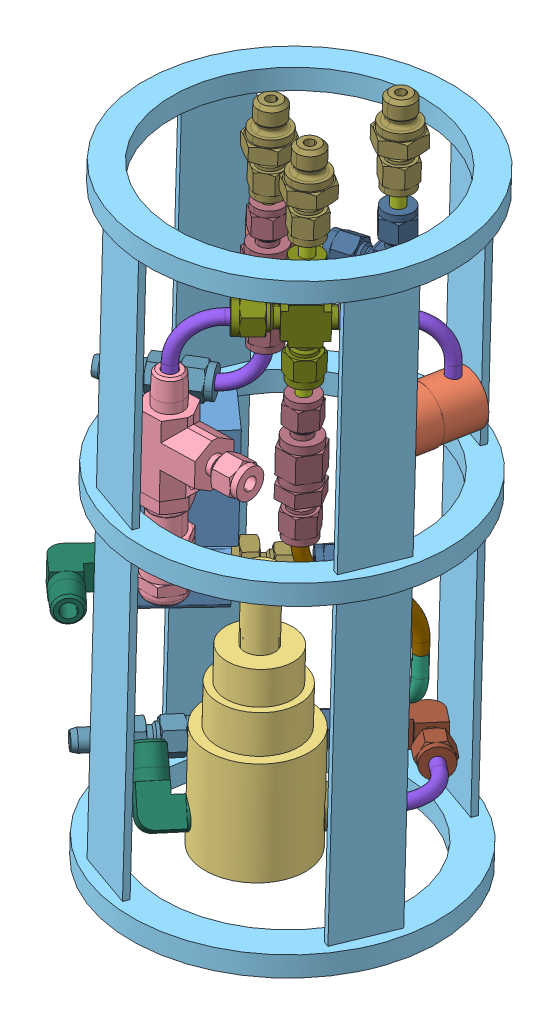
SolidWorks assembly assemblage pressurant bay, configuration Défaut. Lengths in mm.
Overall size (196.95 323.2 205.69).
39 component instances, 16 part files, 39 mates.
Components (placement in the parent):
- 132203_soleno_quart-1: 132203_soleno_quart [Défaut] at (-119.4235 -585.201 211.5274) x (-0.747467 -0.027365 -0.663735) z (0.664276 -0.022565 -0.747147) size (28 80.02 47.02)
- 132201_AG2029_soleno_8-1: 132201_AG2029_soleno_8 [Défaut] at (44.6422 -477.8039 184.1619) x (-0.988898 -0.010608 -0.148214) z (-0.005468 0.999371 -0.035044) size (26.06 49.78 26.06)
- 132201_AG2029_soleno_8-2: 132201_AG2029_soleno_8 [Défaut] at (-39.3498 -434.298 195.0532) x (-0.288649 -0.03513 -0.95679) z (-0.957419 0.004883 0.28866) size (26.06 49.78 26.06)
- 132202_Détendeur-1: 132202_Détendeur [Défaut] at (7.1335 -657.7663 254.7974) x (-0.783042 -0.026076 -0.621422) z (-0.005468 0.999371 -0.035044) size (50 50 118.8)
- SS-4R3A1-SwagelokCompany-3D-11-18-2022.stp-1: SS-4R3A1-SwagelokCompany-3D-11-18-2022.stp [Défaut] at (-26.3083 -491.3399 265.237) x (0.99971 0.004641 -0.023651) z (0.005468 -0.999371 0.035044) size (51.64 20.24 98.81)
- 132300_pressurant_bay_mockup-1: 132300_pressurant_bay_mockup [Défaut] at (-4.8119 -683.7166 228.9256) x (0.341839 -0.031065 -0.939245) z (0.939743 0.017116 0.341454) size (152.4 300 152.4)
- 132102_tuyau_180deg-2: 132102_tuyau_180deg [Défaut] at (20.7227 -597.9813 192.7678) x (-0.926897 -0.018217 -0.374875) z (-0.375277 0.030432 0.926413) size (36.35 28.17 6.35)
- 132103_tuyau_droit-2: 132103_tuyau_droit [Défaut] at (6.0364 -455.1823 182.1277) x (-0.005468 0.999371 -0.035044) z (-0.001435 0.035037 0.999385) size (30 6.35 6.35)
- 132103_tuyau_droit-3: 132103_tuyau_droit [Défaut] at (6.4308 -527.2611 184.6552) x (-0.005468 0.999371 -0.035044) z (-0.041186 -0.03524 -0.99853) size (30 6.35 6.35)
- 132103_tuyau_droit-4: 132103_tuyau_droit [Défaut] at (6.4876 -421.5338 227.8474) x (-0.005468 0.999371 -0.035044) z (-0.001435 0.035037 0.999385) size (30 6.35 6.35)
- 132103_tuyau_droit-5: 132103_tuyau_droit [Défaut] at (5.7292 -399.0439 180.1592) x (-0.005468 0.999371 -0.035044) z (-0.001435 0.035037 0.999385) size (30 6.35 6.35)
- 132103_tuyau_droit-7: 132103_tuyau_droit [Défaut] at (6.3506 -396.4974 226.9695) x (-0.005468 0.999371 -0.035044) z (0.996345 0.002458 -0.085384) size (30 6.35 6.35)
- 132103_tuyau_droit-9: 132103_tuyau_droit [Défaut] at (-23.2756 -392.0235 216.7844) x (-0.005468 0.999371 -0.035044) z (0.001495 0.035053 0.999384) size (30 6.35 6.35)
- 132103_tuyau_droit-12: 132103_tuyau_droit [Défaut] at (6.7101 -462.1929 229.2732) x (-0.005468 0.999371 -0.035044) z (0.919834 -0.00872 -0.392211) size (30 6.35 6.35)
- 132103_tuyau_droit-16: 132103_tuyau_droit [Défaut] at (-11.9207 -441.383 187.0384) x (0.957419 -0.004883 -0.28866) z (-0.209798 -0.698629 -0.684034) size (30 6.35 6.35)
- 132101_tuyau_90deg-4: 132101_tuyau_90deg [Défaut] at (30.286 -459.4562 204.3322) x (-0.688847 0.021639 0.724584) z (-0.724886 -0.028102 -0.688295) size (52.38 52.38 6.35)
- 132101_tuyau_90deg-5: 132101_tuyau_90deg [Défaut] at (-13.2667 -458.0881 250.1444) x (0.688847 -0.021639 -0.724584) z (0.724886 0.028102 0.688295) size (52.38 52.38 6.35)
- 132101_tuyau_90deg-6: 132101_tuyau_90deg [Défaut] at (-38.9599 -470.4239 229.9776) x (-0.839316 0.014464 0.543451) z (0.543616 0.032385 0.838709) size (52.38 52.38 6.35)
- 132105_tuyau_S_2-2: 132105_tuyau_S_2 [Défaut] at (34.5408 -582.1179 197.8443) x (-0.606708 0.024542 0.794546) z (-0.794906 -0.025607 -0.606192) size (51.2 56 6.4)
- 132006_raccord_T_4_SS-400-3-1: 132006_raccord_T_4_SS-400-3 [Défaut] at (-42.4245 -645.2228 233.0351) x (0.621944 -0.024043 -0.782692) z (-0.027001 0.998276 -0.052121) size (53.85 14.22 35.14)
- 132103_tuyau_droit-17: 132103_tuyau_droit [Défaut] at (3.8411 -647.0113 174.8117) x (0.621944 -0.024043 -0.782692) z (0.483638 -0.774308 0.408095) size (30 6.35 6.35)
- 132002_SS-400-9_raccord_L_4-1: 132002_SS-400-9_raccord_L_4 [Défaut] at (30.033 -645.7675 185.0656) x (-0.782596 -0.05355 -0.620223) z (0.621944 -0.024043 -0.782692) size (35.14 14.22 35.14)
- 132005_raccord_SW_G_4_SS-400-1-4RP-1: 132005_raccord_SW_G_4_SS-400-1-4RP [Défaut] at (5.7707 -406.6319 180.4252) x (-0.005468 0.999371 -0.035044) z (-0.009624 0.03499 0.999341) size (40.39 19.05 22)
- 132005_raccord_SW_G_4_SS-400-1-4RP-2: 132005_raccord_SW_G_4_SS-400-1-4RP [Défaut] at (-23.2018 -405.4989 217.257) x (-0.005468 0.999371 -0.035044) z (-0.009624 0.03499 0.999341) size (40.39 19.05 22)
- 132005_raccord_SW_G_4_SS-400-1-4RP-3: 132005_raccord_SW_G_4_SS-400-1-4RP [Défaut] at (6.3971 -404.9859 227.2671) x (-0.005468 0.999371 -0.035044) z (-0.009624 0.03499 0.999341) size (40.39 19.05 22)
- 132003_check_valve_SS-CHS4-25-1: 132003_check_valve_SS-CHS4-25 [Défaut] at (-23.1838 -408.7866 217.3722) x (0.005468 -0.999371 0.035044) z (-0.050941 0.034721 0.998098) size (61.72 17.46 20.16)
- 132010_SS-QF4-S-400_quick_fitting-1: 132010_SS-QF4-S-400_quick_fitting [Défaut] at (-37.4625 -489.6358 229.7489) x (-0.839316 0.014464 0.543451) z (-0.542446 -0.088602 -0.835406) size (44.96 14.3 16.5)
- 132006_raccord_T_4_SS-400-3-2: 132006_raccord_T_4_SS-400-3 [Défaut] at (5.8141 -414.5671 180.7035) x (0.005468 -0.999371 0.035044) z (0.957419 -0.004883 -0.28866) size (53.85 14.22 35.14)
- 132003_check_valve_SS-CHS4-25-2: 132003_check_valve_SS-CHS4-25 [Défaut] at (6.1248 -471.3388 182.6943) x (0.005468 -0.999371 0.035044) z (-0.406496 0.029797 0.913167) size (61.72 17.46 20.16)
- 132005_raccord_SW_G_4_SS-400-1-4RP-4: 132005_raccord_SW_G_4_SS-400-1-4RP [Défaut] at (-12.5558 -568.0822 207.72) x (-0.664276 0.022565 0.747147) z (-0.747318 0.001243 -0.664466) size (40.39 19.05 22)
- 132003_check_valve_SS-CHS4-25-3: 132003_check_valve_SS-CHS4-25 [Défaut] at (6.7652 -472.2552 229.626) x (0.005468 -0.999371 0.035044) z (-0.474344 0.028259 0.879886) size (61.72 17.46 20.16)
- 132006_raccord_T_4_SS-400-3-3: 132006_raccord_T_4_SS-400-3 [Défaut] at (6.5105 -541.8278 185.166) x (0.005468 -0.999371 0.035044) z (0.664276 -0.022565 -0.747147) size (53.85 14.22 35.14)
- 132007_SS-4-ME_raccord_L_NPT-3: 132007_SS-4-ME_raccord_L_NPT [Défaut] at (-29.1208 -621.4599 272.2373) x (0.49179 -0.765825 0.414312) z (-0.621944 0.024043 0.782692) size (33.53 13.72 33.53)
- 132010_SS-QF4-S-400_quick_fitting-2: 132010_SS-QF4-S-400_quick_fitting [Défaut] at (-43.6684 -645.1747 234.6004) x (-0.621944 0.024043 0.782692) z (-0.765639 0.191002 -0.61426) size (44.96 14.3 16.5)
- 132103_tuyau_droit-18: 132103_tuyau_droit [Défaut] at (-44.2794 -645.1511 235.3694) x (0.621944 -0.024043 -0.782692) z (0.778247 0.129642 0.61443) size (30 6.35 6.35)
- 132005_raccord_SW_G_4_SS-400-1-4RP-5: 132005_raccord_SW_G_4_SS-400-1-4RP [Défaut] at (39.6752 -644.0369 213.2161) x (-0.621944 0.024043 0.782692) z (-0.762062 -0.248509 -0.597917) size (40.39 19.05 22)
- 132101_tuyau_90deg-7: 132101_tuyau_90deg [Défaut] at (22.7076 -644.99 203.7515) x (-0.782596 -0.05355 -0.620223) z (0.027001 -0.998276 0.052121) size (52.38 52.38 6.35)
- 132007_SS-4-ME_raccord_L_NPT-4: 132007_SS-4-ME_raccord_L_NPT [Défaut] at (-53.1719 -566.7025 253.4032) x (-0.664276 0.022565 0.747147) z (-0.747342 -0.000323 -0.66444) size (33.53 13.72 33.53)
- 132009_SS-400-4_raccord_X_Sw-1: 132009_SS-400-4_raccord_X_Sw [Défaut] at (6.4389 -412.6201 227.5348) x (0.005468 -0.999371 0.035044) z (-0.688847 0.021639 0.724584) size (53.85 14.22 53.85)
Mates (geometry in assembly coordinates):
- Coaxiale62: concentric aligned: cylinder of tuyau droit basique-4 through (6.6566 -452.4163 228.9303) axis (-0.005468 0.999371 -0.035044) radius 3.175; cylinder of tuyau droit basique-12 through (6.8791 -493.0754 230.3561) axis (-0.005468 0.999371 -0.035044) radius 3.175
- Coaxiale63: concentric aligned: cylinder of tuyau droit basique-4 through (6.6566 -452.4163 228.9303) axis (-0.005468 0.999371 -0.035044) radius 3.175; cylinder of tuyau droit basique-7 through (6.5196 -427.3799 228.0524) axis (-0.005468 0.999371 -0.035044) radius 3.175
- Parallèle3: parallel aligned: cylinder of tuyau droit basique-7 through (6.5196 -427.3799 228.0524) axis (-0.005468 0.999371 -0.035044) radius 3.175; cylinder of tuyau droit basique-9 through (-23.1066 -422.9061 217.8674) axis (-0.005468 0.999371 -0.035044) radius 3.175
- Parallèle4: parallel aligned: cylinder of AG2029-2 through (-39.1054 -478.9699 196.6197) axis (-0.005468 0.999371 -0.035044) radius 13.03; cylinder of tuyau droit basique-2 through (6.2053 -486.0649 183.2107) axis (-0.005468 0.999371 -0.035044) radius 3.175
- Parallèle10: parallel anti-aligned: cylinder of tuyau droit basique-7 through (6.5196 -427.3799 228.0524) axis (-0.005468 0.999371 -0.035044) radius 3.175; cylinder of tuyau coudé 90deg-4 through (43.5119 -459.8717 190.4202) axis (0.005468 -0.999371 0.035044) radius 3.175
- Coaxiale94: concentric aligned: cone of AG2029-1 through (43.5402 -465.0412 190.6015) axis (0.005468 -0.999371 0.035044); cylinder of tuyau coudé 90deg-4 through (43.5119 -459.8717 190.4202) axis (0.005468 -0.999371 0.035044) radius 3.175
- Distance13: distance = 0 mm anti-aligned: plane of tuyau demi circulaire-2 through (34.5714 -587.7144 198.0405) normal (-0.005468 0.999371 -0.035044); plane of tuyau en S-2 through (34.5714 -587.7144 198.0405) normal (0.005468 -0.999371 0.035044)
- Coaxiale95: concentric anti-aligned: cylinder of tuyau demi circulaire-2 through (34.5714 -587.7144 198.0405) axis (0.005468 -0.999371 0.035044) radius 3.175; cylinder of tuyau en S-2 through (34.5714 -587.7144 198.0405) axis (-0.005468 0.999371 -0.035044) radius 3.2
- Coaxiale100: concentric anti-aligned: cylinder of SS-4R3A1-SwagelokCompany-3D-11-18-2022.stp-1 through (-26.4323 -468.6796 264.4424) axis (-0.005468 0.999371 -0.035044) radius 3.556; cylinder of tuyau coudé 90deg-5 through (-26.4926 -457.6726 264.0564) axis (0.005468 -0.999371 0.035044) radius 3.175
- Parallèle17: parallel aligned: cylinder of Détendeur Azote-1 through (6.8535 -606.5985 253.0031) axis (0.005468 -0.999371 0.035044) radius 25; line of pressurant_bay_mockup-1 through (-42.8298 -521.9796 281.5208) axis (0.005468 -0.999371 0.035044)
- Coaxiale110: concentric aligned: cylinder of 132006_raccord_T_4_SS-400-3-1 through (-37.6853 -645.406 227.0709) axis (0.621944 -0.024043 -0.782692) radius 3.175; cylinder of 132103_tuyau_droit-17 through (-15.3782 -646.2683 198.9984) axis (0.621944 -0.024043 -0.782692) radius 3.175
- Coaxiale112: concentric aligned: cylinder of 132103_tuyau_droit-17 through (-15.3782 -646.2683 198.9984) axis (0.621944 -0.024043 -0.782692) radius 3.175; cylinder of 132002_SS-400-9_raccord_L_4-1 through (-3.0436 -646.7451 183.4758) axis (0.621944 -0.024043 -0.782692) radius 3.175
- Parallèle22: parallel aligned: plane of 132006_raccord_T_4_SS-400-3-1 through (-36.5073 -639.6512 214.8494) normal (-0.782596 -0.05355 -0.620223); plane of 132002_SS-400-9_raccord_L_4-1 through (1.1494 -647.4394 168.0068) normal (-0.782596 -0.05355 -0.620223)
- Coaxiale115: concentric aligned: cylinder of 132103_tuyau_droit-5 through (5.8982 -429.9264 181.2421) axis (-0.005468 0.999371 -0.035044) radius 3.175; cylinder of 132005_raccord_SW_G_4_SS-400-1-4RP-1 through (5.729 -399.0167 180.1582) axis (-0.005468 0.999371 -0.035044) radius 3.175
- Coaxiale116: concentric aligned: cylinder of 132103_tuyau_droit-7 through (6.5196 -427.3799 228.0524) axis (-0.005468 0.999371 -0.035044) radius 3.175; cylinder of 132005_raccord_SW_G_4_SS-400-1-4RP-3 through (6.3554 -397.3707 227.0001) axis (-0.005468 0.999371 -0.035044) radius 3.175
- Coaxiale117: concentric aligned: cylinder of 132103_tuyau_droit-9 through (-23.1066 -422.9061 217.8674) axis (-0.005468 0.999371 -0.035044) radius 3.175; cylinder of 132005_raccord_SW_G_4_SS-400-1-4RP-2 through (-23.2435 -397.8837 216.9899) axis (-0.005468 0.999371 -0.035044) radius 3.175
- Coïncidente12: coincident aligned: plane of 132005_raccord_SW_G_4_SS-400-1-4RP-1 through (5.5733 -366.3565 176.5783) normal (-0.005468 0.999371 -0.035044); plane of 132005_raccord_SW_G_4_SS-400-1-4RP-2 through (-23.3993 -365.2235 213.41) normal (-0.005468 0.999371 -0.035044)
- Coïncidente13: coincident aligned: plane of 132005_raccord_SW_G_4_SS-400-1-4RP-2 through (-23.3993 -365.2235 213.41) normal (-0.005468 0.999371 -0.035044); plane of 132005_raccord_SW_G_4_SS-400-1-4RP-3 through (6.1997 -364.7105 223.4202) normal (-0.005468 0.999371 -0.035044)
- Coaxiale118: concentric anti-aligned: cylinder of 132103_tuyau_droit-9 through (-23.1066 -422.9061 217.8674) axis (-0.005468 0.999371 -0.035044) radius 3.175; cylinder of 132003_check_valve_SS-CHS4-25-1 through (-23.1422 -416.4018 217.6393) axis (0.005468 -0.999371 0.035044) radius 3.175
- Coaxiale120: concentric aligned: cylinder of 132101_tuyau_90deg-6 through (-64.0344 -489.1779 246.954) axis (0.839316 -0.014464 -0.543451) radius 3.175; cylinder of 132010_SS-QF4-S-400_quick_fitting-1 through (-66.8822 -489.1288 248.7979) axis (0.839316 -0.014464 -0.543451) radius 3.048
- Coaxiale121: concentric aligned: cylinder of 132103_tuyau_droit-16 through (-41.5068 -441.2321 195.9586) axis (0.957419 -0.004883 -0.28866) radius 3.175; cylinder of 132006_raccord_T_4_SS-400-3-2 through (-12.5207 -441.3799 187.2193) axis (0.957419 -0.004883 -0.28866) radius 3.175
- Coaxiale122: concentric anti-aligned: cylinder of 132103_tuyau_droit-5 through (5.8982 -429.9264 181.2421) axis (-0.005468 0.999371 -0.035044) radius 3.175; cylinder of 132006_raccord_T_4_SS-400-3-2 through (5.8558 -422.1823 180.9705) axis (0.005468 -0.999371 0.035044) radius 3.175
- Coaxiale123: concentric aligned: cylinder of 132103_tuyau_droit-2 through (6.2053 -486.0649 183.2107) axis (-0.005468 0.999371 -0.035044) radius 3.175; cylinder of 132003_check_valve_SS-CHS4-25-2 through (6.4206 -525.4067 184.5902) axis (-0.005468 0.999371 -0.035044) radius 3.175
- Coaxiale125: concentric anti-aligned: cylinder of 132203_soleno_quart-1 through (-61.3456 -566.4248 262.5965) axis (-0.664276 0.022565 0.747147) radius 3.3782; cylinder of 132005_raccord_SW_G_4_SS-400-1-4RP-4 through (-36.1671 -567.2801 234.2769) axis (0.664276 -0.022565 -0.747147) radius 6.5785
- Coïncidente14: coincident anti-aligned: plane of 132203_soleno_quart-1 through (-89.5311 -586.2164 177.9058) normal (0.664276 -0.022565 -0.747147); plane of 132005_raccord_SW_G_4_SS-400-1-4RP-4 through (-31.4531 -567.4402 228.9749) normal (-0.664276 0.022565 0.747147)
- Coaxiale127: concentric anti-aligned: cylinder of 132103_tuyau_droit-12 through (6.8791 -493.0754 230.3561) axis (-0.005468 0.999371 -0.035044) radius 3.175; cylinder of 132003_check_valve_SS-CHS4-25-3 through (6.8068 -479.8704 229.8931) axis (0.005468 -0.999371 0.035044) radius 3.175
- Coaxiale130: concentric aligned: cylinder of 132101_tuyau_90deg-6 through (-22.845 -470.7016 219.5434) axis (-0.005468 0.999371 -0.035044) radius 3.175; cylinder of 132003_check_valve_SS-CHS4-25-1 through (-22.888 -462.8546 219.2682) axis (-0.005468 0.999371 -0.035044) radius 3.175
- Coaxiale135: concentric anti-aligned: cylinder of 132202_Détendeur-1 through (24.155 -643.4369 232.7477) axis (-0.621944 0.024043 0.782692) radius 6.35; cylinder of 132007_SS-4-ME_raccord_L_NPT-3 through (-4.114 -642.3441 268.3231) axis (0.621944 -0.024043 -0.782692) radius 3.556
- Coaxiale138: concentric aligned: cylinder of 132006_raccord_T_4_SS-400-3-1 through (-37.6853 -645.406 227.0709) axis (0.621944 -0.024043 -0.782692) radius 3.175; cylinder of 132103_tuyau_droit-18 through (-63.4987 -644.4081 259.5562) axis (0.621944 -0.024043 -0.782692) radius 3.175
- Coaxiale139: concentric aligned: cylinder of 132010_SS-QF4-S-400_quick_fitting-2 through (-65.4688 -644.3319 262.0354) axis (0.621944 -0.024043 -0.782692) radius 3.048; axis of 132103_tuyau_droit-18 through (-63.4987 -644.4081 259.5562) axis (0.621944 -0.024043 -0.782692)
- Distance16: distance = 2 mm anti-aligned: plane of 132010_SS-QF4-S-400_quick_fitting-2 through (-46.391 -644.4955 232.4161) normal (0.621944 -0.024043 -0.782692); plane of 132006_raccord_T_4_SS-400-3-1 through (-42.5205 -641.6729 232.8497) normal (-0.621944 0.024043 0.782692)
- Coaxiale140: concentric anti-aligned: cylinder of 132202_Détendeur-1 through (24.155 -643.4369 232.7477) axis (-0.621944 0.024043 0.782692) radius 6.35; cylinder of 132005_raccord_SW_G_4_SS-400-1-4RP-5 through (17.5686 -643.1823 241.0364) axis (0.621944 -0.024043 -0.782692) radius 6.5785
- Coaxiale143: concentric aligned: cylinder of 132005_raccord_SW_G_4_SS-400-1-4RP-5 through (34.936 -643.8537 219.1802) axis (-0.621944 0.024043 0.782692) radius 3.175; cylinder of 132101_tuyau_90deg-7 through (37.7334 -643.9618 215.6598) axis (-0.621944 0.024043 0.782692) radius 3.175
- Coaxiale145: concentric anti-aligned: cylinder of 132002_SS-400-9_raccord_L_4-1 through (24.0696 -646.1755 180.3395) axis (-0.782596 -0.05355 -0.620223) radius 3.175; cylinder of 132101_tuyau_90deg-7 through (11.171 -647.0581 170.1171) axis (0.782596 0.05355 0.620223) radius 3.175
- Coaxiale147: concentric anti-aligned: cylinder of 132203_soleno_quart-1 through (-61.3456 -566.4248 262.5965) axis (-0.664276 0.022565 0.747147) radius 3.3782; cylinder of 132007_SS-4-ME_raccord_L_NPT-4 through (-58.1882 -566.5321 259.0452) axis (0.664276 -0.022565 -0.747147) radius 3.556
- Coaxiale148: concentric anti-aligned: cylinder of 132103_tuyau_droit-4 through (6.6566 -452.4163 228.9303) axis (-0.005468 0.999371 -0.035044) radius 3.175; cylinder of 132009_SS-400-4_raccord_X_Sw-1 through (6.4805 -420.2353 227.8019) axis (0.005468 -0.999371 0.035044) radius 3.175
- Coaxiale149: concentric anti-aligned: cylinder of 132101_tuyau_90deg-5 through (7.2937 -439.5493 227.734) axis (-0.688847 0.021639 0.724584) radius 3.175; cylinder of 132009_SS-400-4_raccord_X_Sw-1 through (-6.7114 -439.1094 242.4657) axis (0.688847 -0.021639 -0.724584) radius 3.175
- Coaxiale150: concentric aligned: cylinder of 132102_tuyau_180deg-2 through (6.8192 -598.2546 187.1447) axis (-0.005468 0.999371 -0.035044) radius 3.175; cylinder of 132006_raccord_T_4_SS-400-3-3 through (6.7633 -588.0267 186.7861) axis (-0.005468 0.999371 -0.035044) radius 3.175
- Coaxiale151: concentric aligned: cylinder of 132105_tuyau_S_2-2 through (7.1153 -536.2466 231.87) axis (-0.005468 0.999371 -0.035044) radius 3.2; cylinder of 132003_check_valve_SS-CHS4-25-3 through (7.061 -526.3231 231.522) axis (-0.005468 0.999371 -0.035044) radius 3.175
